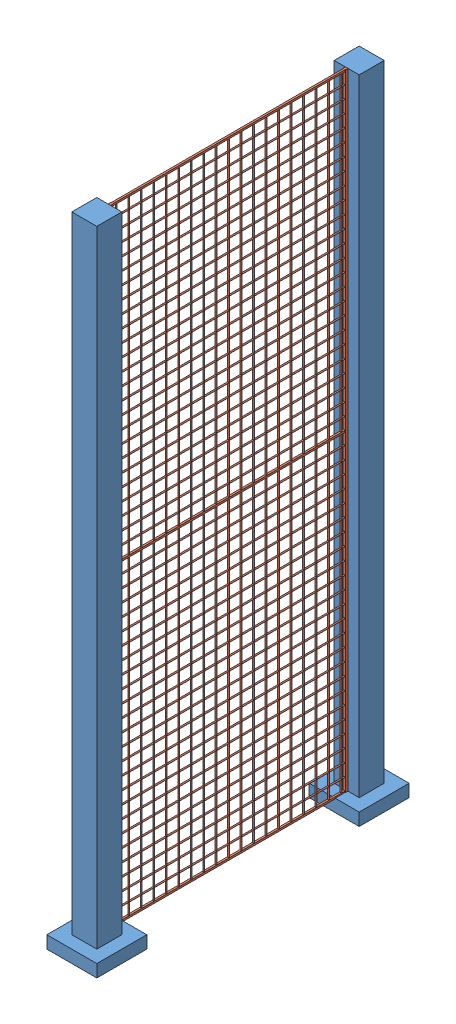
SolidWorks assembly Assieme2, configuration Default. Lengths in mm.
Overall size (200 2555 1250).
3 component instances, 2 part files, 7 mates.
Components (placement in the parent):
- palo_barriera-1: palo_barriera [Default] at (0 0 1050) size (200 2555 200)
- palo_barriera-2: palo_barriera [Default] at origin size (200 2555 200)
- rete_1m-1: rete_1m [Default] at (0 51.25 972.5) x (0 0 -1) z (0 1 0) size (950 10 2507.5)
Mates (geometry in assembly coordinates):
- Coincidente1: coordinate: point of palo_barriera-2
- Coincidente2: coincident: plane of palo_barriera-1 through (0 2555 1050) normal (0 1 0); plane of palo_barriera-2 through (0 2555 0) normal (0 1 0)
- Coincidente3: coincident: plane of palo_barriera-1 through (-50 2550 1000) normal (-1 0 0); plane of palo_barriera-2 through (-50 2550 -50) normal (-1 0 0)
- Coincidente4: coincident: plane of palo_barriera-2 through (-50 2550 50) normal (0 0 1); plane of rete_1m-1 through (0 51.25 50) normal (0 0 -1)
- Coincidente5: coincident: plane of palo_barriera-2 through (0 2555 0) normal (0 1 0); plane of rete_1m-1 through (-3.75 2555 39.3934) normal (0 1 0)
- Distanza1: distance = 45 mm aligned: plane of rete_1m-1 through (-5 2569.1421 60) normal (-1 0 0); plane of palo_barriera-2 through (-50 2550 -50) normal (-1 0 0)
- Coincidente7: coincident anti-aligned: plane of palo_barriera-1 through (-50 2550 1000) normal (0 0 -1); plane of rete_1m-1 through (0 51.25 1000) normal (0 0 1)
